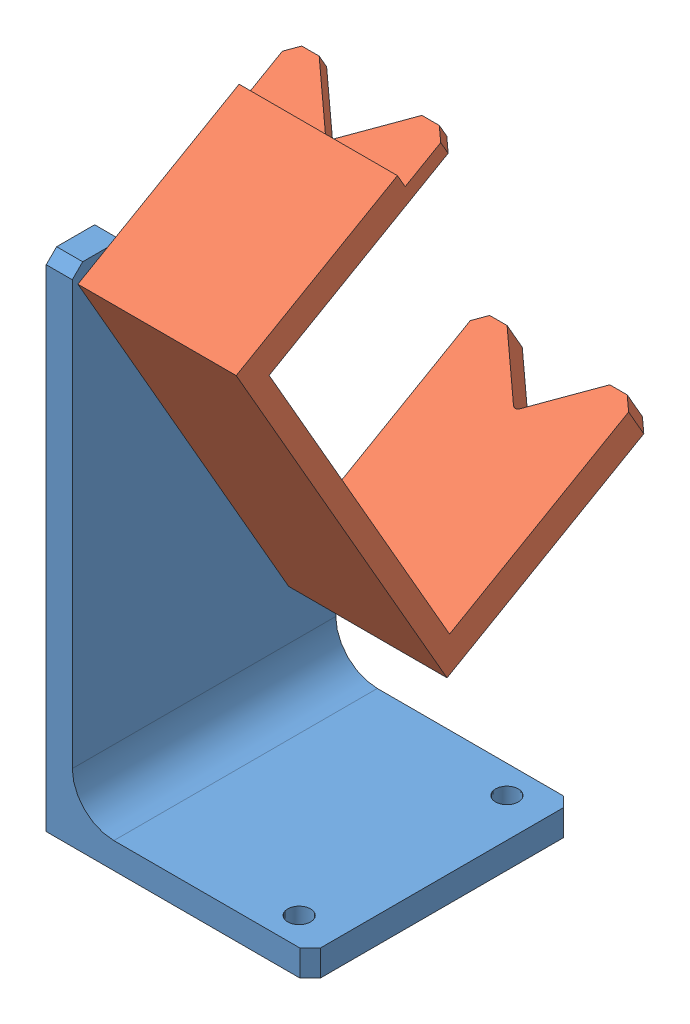
SolidWorks assembly Montagem1, configuration Valor predeterminado. Lengths in mm.
Overall size (63.5 144.96 101.57).
2 component instances, 2 part files, 1 mates.
Components (placement in the parent):
- porta_pen1-1: porta_pen1 [Valor predeterminado] at (-20.9122 -47.8079 0) size (63.5 120.63 63.4)
- pen_holder2-1: pen_holder2 [Valor predeterminado] at (-27.3522 24.562 4.9969) x (0 0.867217 0.497931) z (-1 0 0) size (101.86 57.09 38.1)
Mates (geometry in assembly coordinates):
- Coincidente1: coincident: plane of assembly; plane of assembly; plane of porta_pen1-1 through (-46.4022 -47.8079 0) normal (1 0 0); plane of pen_holder2-1 through (-46.4022 97.1562 -19.1529) normal (-1 0 0)
